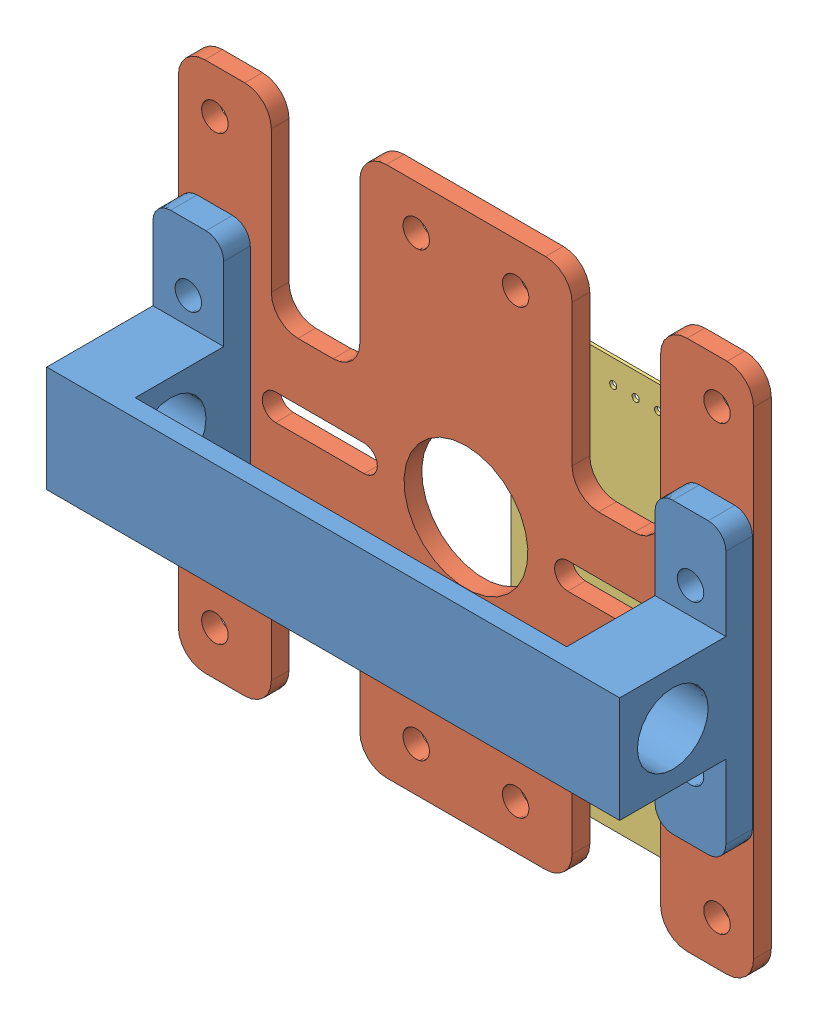
SolidWorks assembly 电池电路板装配体, configuration 默认. Lengths in mm.
Overall size (65 60 18.98).
3 component instances, 3 part files, 7 mates.
Components (placement in the parent):
- 电池固定-1: 电池固定 [默认] at (-103.9748 70.2988 -5.5) x (0 1 0) z (0 0 1) size (32.68 64.74 15)
- 电路板固定-1: 电路板固定 [默认] at (-101.9656 66.5721 -8.5) x (1 0 0) z (0 1 0) size (65 2 60)
- newPCB-1: newPCB [默认] at (-168.1044 -56.9268 -10.8454) x (0.000017 1 0) z (0 0 -1) size (56.13 28.07 1.98)
Mates (geometry in assembly coordinates):
- 同心1: concentric: cylinder of assembly; cylinder of assembly; cylinder of 电池固定-1 through (-130.3334 57.5721 -8.5) axis (0 0 1) radius 1.5; cylinder of 电路板固定-1 through (-130.3334 57.5721 -8.5) axis (0 0 -1) radius 1.5
- 同心2: concentric: cylinder of assembly; cylinder of assembly; cylinder of 电池固定-1 through (-130.3334 75.5721 -8.5) axis (0 0 1) radius 1.5; cylinder of 电路板固定-1 through (-130.3334 75.5721 -8.5) axis (0 0 -1) radius 1.5
- 重合1: coincident: plane of assembly; plane of assembly; plane of 电池固定-1 through (-103.9748 70.2988 -8.5) normal (0 0 -1); plane of 电路板固定-1 through (-101.9656 66.5721 -8.5) normal (0 0 1)
- 平行1: parallel: cylinder of assembly; cylinder of assembly; cylinder of 电池固定-1 through (-73.5934 75.5721 -8.5) axis (0 0 1) radius 1.5; cylinder of 电路板固定-1 through (-73.5977 75.5721 -8.5) axis (0 0 -1) radius 1.5
- 重合2: coincident: plane of assembly; plane of assembly; plane of 电路板固定-1 through (-101.9656 66.5721 -10.5) normal (0 0 -1); plane of newPCB-1 through (-98.8878 39.5911 -10.5) normal (0 0 1)
- 同心4: concentric: circle of assembly; circle of assembly; circle of 电路板固定-1; circle of newPCB-1
- 同心5: concentric: circle of assembly; circle of assembly; circle of 电路板固定-1; circle of newPCB-1
